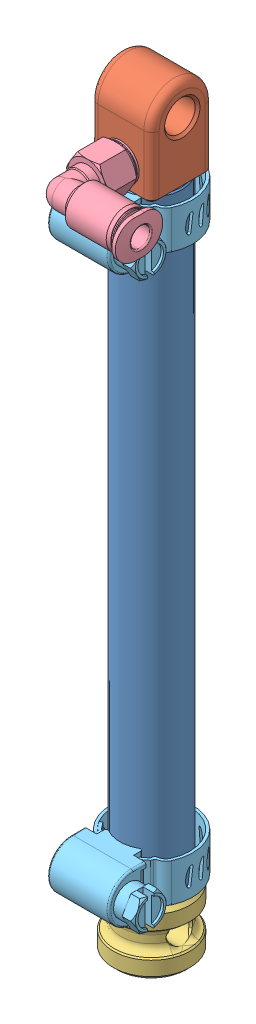
SolidWorks assembly AARL_QR_PN_PA_BL_AN_EX-Extensor, configuration Default. Lengths in mm.
Overall size (24.22 158.75 31.28).
6 component instances, 5 part files, 15 mates.
Components (placement in the parent):
- AARL_QR_PN_PA_BL_AN_EX_001-1: AARL_QR_PN_PA_BL_AN_EX_001 [Resting] at origin size (12.7 127 12.7)
- AARL_QR_PN_EP_001-1: AARL_QR_PN_EP_001 [Default] at (0 76.2 0) x (0 0 1) z (-1 0 0) size (12.7 31.75 12.7)
- AARL_QR_PN_EP_002-1: AARL_QR_PN_EP_002 [Default] at (0 -63.5 0) x (-1 0 0) z (0 0 1) size (15.88 25.4 15.88)
- AARL_Puppy_18_02_57_010-QSML-M3-4-1: AARL_Puppy_18_02_57_010-QSML-M3-4 [Default] at (0 68.2625 17.85) x (1 0 0) z (0 0 -1) size (20.32 8 18.9)
- AARL_Puppy_18_02_57_011-5388K140_Hose-Clamp-1: AARL_Puppy_18_02_57_011-5388K140_Hose-Clamp [5388K14] at (0 -58.547 0) x (1 0 0) z (0 -1 0) size (19.43 23.71 9.91)
- AARL_Puppy_18_02_57_011-5388K140_Hose-Clamp-2: AARL_Puppy_18_02_57_011-5388K140_Hose-Clamp [5388K14] at (0 58.547 0) x (1 0 0) z (0 -1 0) size (19.43 23.71 9.91)
Mates (geometry in assembly coordinates):
- Concentric1: concentric aligned: cylinder of AARL_QR_PN_PA_BL_AN_EX_001-1 through (0 11.6086 0) axis (0 1 0) radius 4.7625; cylinder of AARL_QR_PN_EP_001-1 through (0 85.744 0) axis (0 1 0) radius 4.3656
- Parallel1: parallel aligned: plane of AARL_QR_PN_EP_001-1 through (-6.35 63.5 6.35) normal (0 0 1)
- Coincident2: coincident anti-aligned: plane of AARL_QR_PN_PA_BL_AN_EX_001-1 through (4.7625 63.5 0) normal (0 1 0); plane of AARL_QR_PN_EP_001-1 through (-6.35 63.5 -6.35) normal (0 -1 0)
- Concentric2: concentric aligned: cylinder of AARL_QR_PN_EP_001-1 through (0 68.2625 6.35) axis (0 0 1) radius 2.0193; cylinder of AARL_Puppy_18_02_57_010-QSML-M3-4-1 through (0 68.2625 6.35) axis (0 0 1) radius 1.5
- Coincident3: coincident anti-aligned: plane of AARL_QR_PN_EP_001-1 through (-6.35 63.5 6.35) normal (0 0 1); plane of AARL_Puppy_18_02_57_010-QSML-M3-4-1 through (0 68.2625 6.35) normal (0 0 -1)
- Parallel2: parallel anti-aligned: plane of AARL_QR_PN_EP_001-1 through (-6.35 63.5 -6.35) normal (0 -1 0); plane of AARL_Puppy_18_02_57_010-QSML-M3-4-1 through (-2.3094 72.2625 13.4056) normal (0 1 0)
- Concentric3: concentric anti-aligned: cylinder of AARL_QR_PN_PA_BL_AN_EX_001-1 through (0 11.6086 0) axis (0 1 0) radius 4.7625; cylinder of AARL_QR_PN_EP_002-1 through (0 -71.2377 0) axis (0 -1 0) radius 4.3656
- Coincident5: coincident anti-aligned: plane of AARL_QR_PN_PA_BL_AN_EX_001-1 through (6.35 -63.5 0) normal (0 -1 0); plane of AARL_QR_PN_EP_002-1 through (-4.3656 -63.5 0) normal (0 1 0)
- Parallel3: parallel anti-aligned: cylinder of AARL_QR_PN_EP_001-1 through (-6.35 76.2 0) axis (1 0 0) radius 3.175; cylinder of AARL_QR_PN_EP_002-1 through (7.9375 -69.85 0) axis (-1 0 0) radius 2.3813
- Concentric5: concentric aligned: cylinder of AARL_QR_PN_PA_BL_AN_EX_001-1 through (0 11.6086 0) axis (0 1 0) radius 6.35; cylinder of AARL_Puppy_18_02_57_011-5388K140_Hose-Clamp-2 through (0 54.5783 0) axis (0 1 0) radius 7.9375
- Coincident6: coincident aligned: plane of AARL_QR_PN_EP_001-1 through (6.35 76.2 0) normal (1 0 0); plane of AARL_Puppy_18_02_57_011-5388K140_Hose-Clamp-2 through (6.35 58.547 10.2337) normal (1 0 0)
- Coincident7: coincident anti-aligned: plane of AARL_QR_PN_EP_001-1 through (-6.35 63.5 -6.35) normal (0 -1 0); plane of AARL_Puppy_18_02_57_011-5388K140_Hose-Clamp-2 through (0 63.5 0) normal (0 1 0)
- Concentric6: concentric aligned: cylinder of AARL_QR_PN_PA_BL_AN_EX_001-1 through (0 11.6086 0) axis (0 1 0) radius 6.35; cylinder of AARL_Puppy_18_02_57_011-5388K140_Hose-Clamp-1 through (0 -62.5157 0) axis (0 1 0) radius 7.9375
- Coincident8: coincident aligned: plane of AARL_Puppy_18_02_57_011-5388K140_Hose-Clamp-1 through (6.35 -58.547 10.2337) normal (1 0 0); plane of AARL_Puppy_18_02_57_011-5388K140_Hose-Clamp-2 through (6.35 58.547 10.2337) normal (1 0 0)
- Coincident9: coincident anti-aligned: plane of AARL_QR_PN_EP_002-1 through (-4.3656 -63.5 0) normal (0 1 0); plane of AARL_Puppy_18_02_57_011-5388K140_Hose-Clamp-1 through (0 -63.5 0) normal (0 -1 0)
